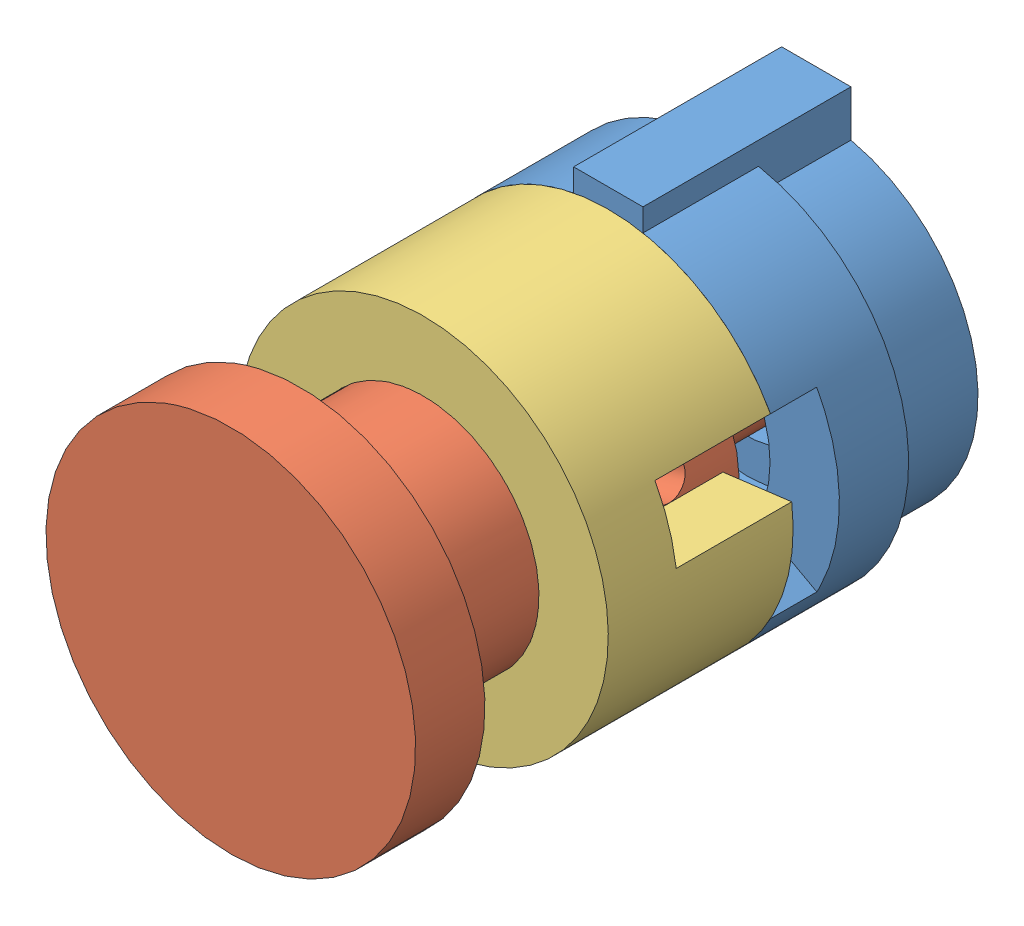
SolidWorks assembly Button, configuration Default. Lengths in mm.
Overall size (20.75 20.75 27).
3 component instances, 3 part files, 4 mates.
Components (placement in the parent):
- buttonBase-1: buttonBase [Default] at (5.3295 10.3881 11.2357) size (16 16.84 9)
- buttonAxle-1: buttonAxle [Default] at (5.3295 10.3881 36.5716) x (-0.293811 0.955863 0) z (0 0 -1) size (16 16 27)
- buttonFrame-2: buttonFrame [Default] at (5.3295 10.3881 28.2357) x (-0.930508 -0.366273 0) z (0 0 -1) size (16 16 8)
Mates (geometry in assembly coordinates):
- Concentric1: concentric anti-aligned: circle of buttonBase-1; circle of buttonAxle-1
- Concentric3: concentric anti-aligned: circle of buttonBase-1; circle of buttonFrame-2
- Coincident1: coincident aligned: plane of buttonBase-1 through (12.3471 14.2291 19.2357) normal (0.480124 -0.877201 0); plane of buttonFrame-2 through (12.3471 14.2291 22.7357) normal (0.480124 -0.877201 0)
- Coincident2: coincident anti-aligned: plane of buttonBase-1 through (5.3295 10.3881 20.2357) normal (0 0 1); plane of buttonFrame-2 through (5.3295 10.3881 20.2357) normal (0 0 -1)
